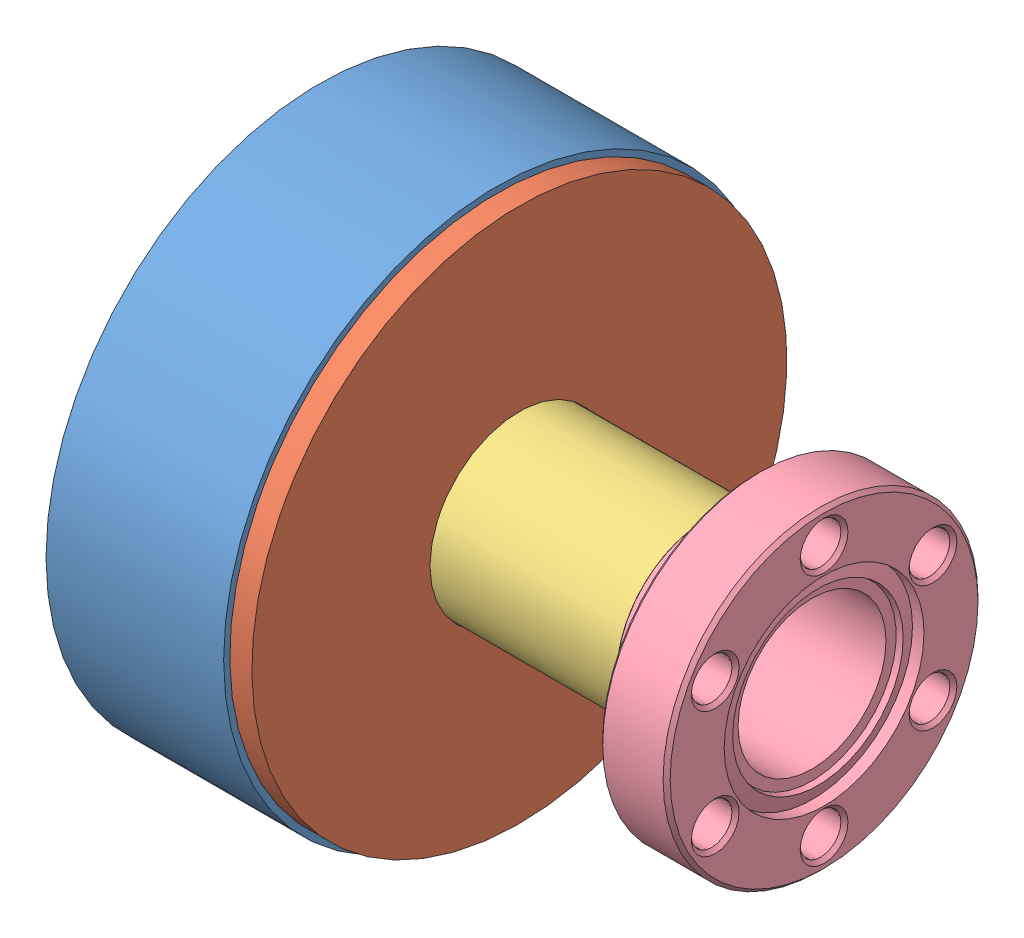
SolidWorks assembly 420032, configuration Default. Lengths in mm.
Overall size (54.1 78.23 78.23).
4 component instances, 4 part files, 7 mates.
Components (placement in the parent):
- 042250-1: 042250 [Default] at (12.5195 29.9417 45.4892) size (19.05 58.72 58.72)
- 942002-1: 942002 [Default] at (33.9317 29.9417 45.4892) x (0 0.492472 0.870329) z (-1 0 0) size (57.4 57.4 2.36)
- 942004-1: 942004 [Default] at (31.5695 29.9417 45.4892) x (0 0.213724 -0.976894) z (1 0 0) size (19.05 19.05 22.35)
- 110004-1: 110004 [Default] at (66.6215 29.9417 45.4892) x (-1 0 0) z (0 0 1) size (14.22 33.78 33.78)
Mates (geometry in assembly coordinates):
- Concentric1: concentric anti-aligned: cylinder of 042250-1 through (12.5195 29.9417 45.4892) axis (-1 0 0) radius 29.3624; cylinder of 942002-1 through (31.5695 29.9417 45.4892) axis (1 0 0) radius 9.5885
- Coincident1: coincident anti-aligned: plane of 042250-1 through (31.5695 29.9417 45.4892) normal (1 0 0); plane of 942002-1 through (31.5695 29.9417 45.4892) normal (-1 0 0)
- Concentric2: concentric anti-aligned: cylinder of 942002-1 through (31.5695 29.9417 45.4892) axis (1 0 0) radius 9.5885; cylinder of 942004-1 through (53.9215 29.9417 45.4892) axis (-1 0 0) radius 9.525
- Coincident2: coincident anti-aligned: plane of 042250-1 through (31.5695 29.9417 45.4892) normal (1 0 0); plane of 942004-1 through (31.5695 29.9417 45.4892) normal (-1 0 0)
- Concentric3: concentric anti-aligned: cylinder of 942004-1 through (53.9215 29.9417 45.4892) axis (-1 0 0) radius 9.525; cylinder of 110004-1 through (66.6215 29.9417 45.4892) axis (1 0 0) radius 9.4996
- Coincident3: coincident anti-aligned: plane of 942004-1 through (53.9215 29.9417 45.4892) normal (1 0 0); plane of 110004-1 through (53.9215 21.4327 45.4892) normal (-1 0 0)
- Parallel1: parallel aligned: plane of 110004-1 through (66.6215 29.9417 45.4892) normal (0 0 1)
